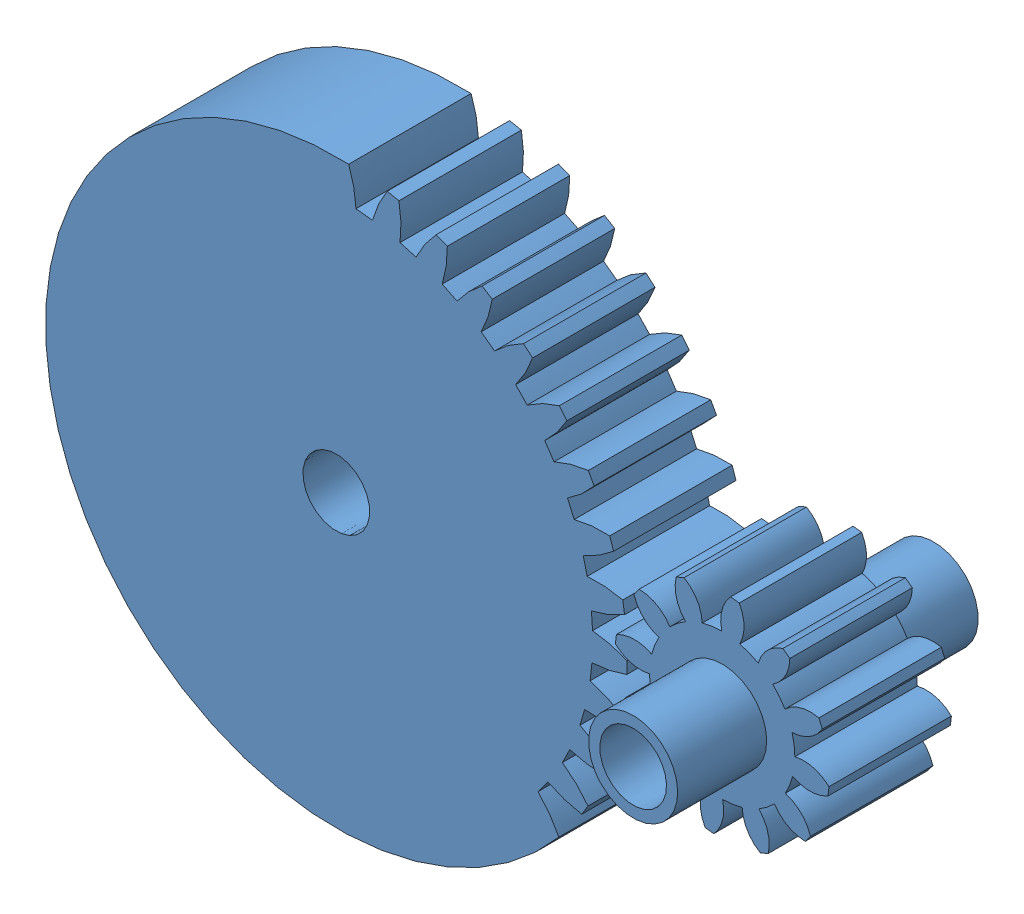
SolidWorks assembly gears 1, configuration Default. Lengths in mm.
Overall size (84.37 72.95 27).
2 component instances, 1 part files, 4 mates.
Components (placement in the parent):
- spur gear_am-2: spur gear_am [Metric - Spur gear 1.375M 36T 14.5PA 11FW ---S12O8H19L6N] x (0 0 1) z (0.591379 0.806394 0) size (19 52.19 52.19)
- spur gear_am-3: spur gear_am [Metric - Spur gear 1.375M 12T 14.5PA 11FW ---S12B8H27L6N] at (34.6667 0 11) x (0 0 -1) z (-0.786419 -0.617694 0) size (27 18.78 18.78)
Mates (geometry in assembly coordinates):
- Coincident1: coincident: plane of spur gear_am-3 through (34.6667 0 0) normal (0 0 -1); plane of assembly through (0 0 0) normal (0 0 1)
- Coincident4: coincident: plane of spur gear_am-2 through (0 0 0) normal (0 0 -1); plane of assembly through (0 0 0) normal (0 0 1)
- Concentric1: concentric: circle of spur gear_am-2; circle of assembly
- Concentric2: concentric: circle of spur gear_am-3; circle of assembly
